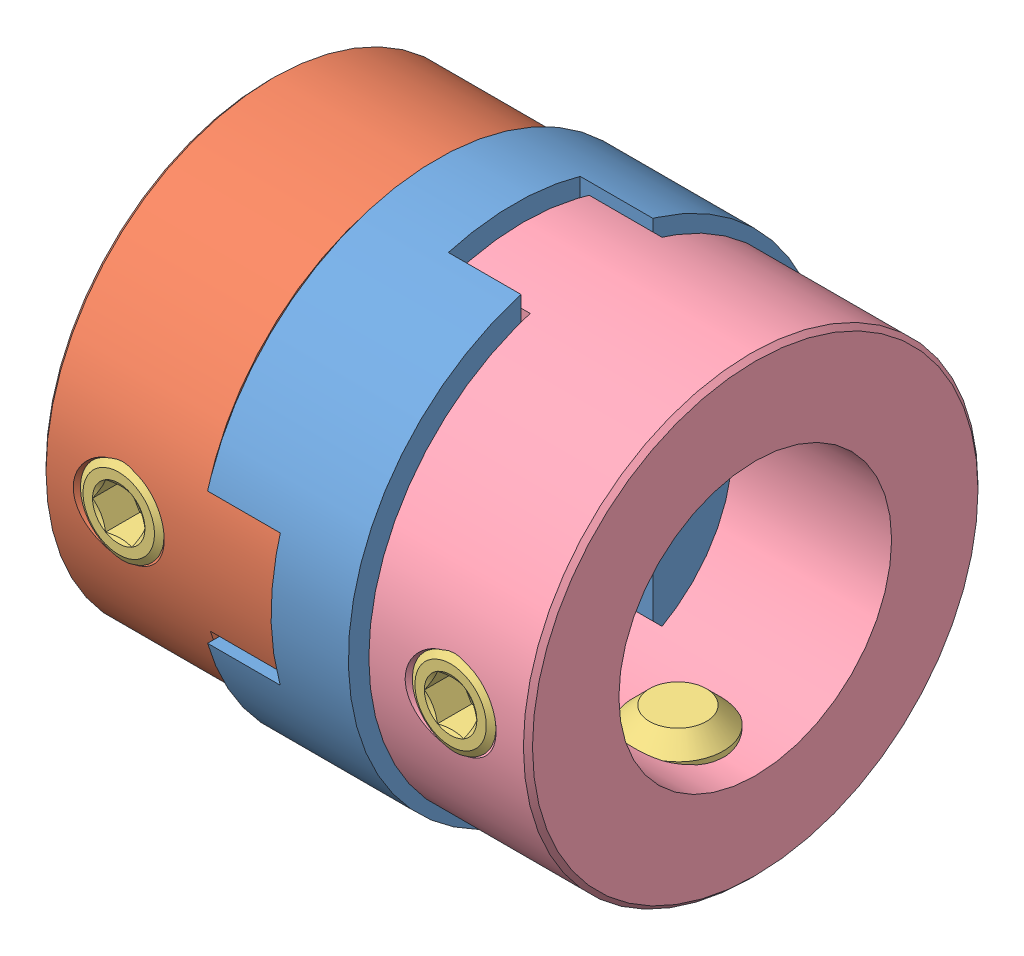
SolidWorks assembly Assem1, configuration Default. Lengths in mm.
Overall size (21.4 21 21).
7 component instances, 4 part files, 0 mates.
Components (placement in the parent):
- MCO_spacer20-1: MCO_spacer20 [Default] at (3.3 0 0) x (-1 0 0) z (0 -1 0) size (6.6 21 21)
- MCO20_6-1: MCO20_6 [Default] at (-10.7 0 0) size (10.2 20 20)
- Hexagon_socket_set_screw_with_flat_point_DIN_913___M4x5-1: Hexagon_socket_set_screw_with_flat_point_DIN_913___M4x5 [Default] at (-7.3 0 10) x (0 0 -1) z (-1 0 0) size (5 4 4)
- Hexagon_socket_set_screw_with_flat_point_DIN_913___M4x5-2: Hexagon_socket_set_screw_with_flat_point_DIN_913___M4x5 [Default] at (-7.3 -10 0) x (0 1 0) z (-1 0 0) size (5 4 4)
- MCO20_12-1: MCO20_12 [Default] at (10.7 0 0) x (-1 0 0) z (0 -1 0) size (10.2 20 20)
- Hexagon_socket_set_screw_with_flat_point_DIN_913___M4x5-3: Hexagon_socket_set_screw_with_flat_point_DIN_913___M4x5 [Default] at (7.3 -10 0) x (0 1 0) z (1 0 0) size (5 4 4)
- Hexagon_socket_set_screw_with_flat_point_DIN_913___M4x5-4: Hexagon_socket_set_screw_with_flat_point_DIN_913___M4x5 [Default] at (7.3 0 10) x (0 0 -1) z (1 0 0) size (5 4 4)
